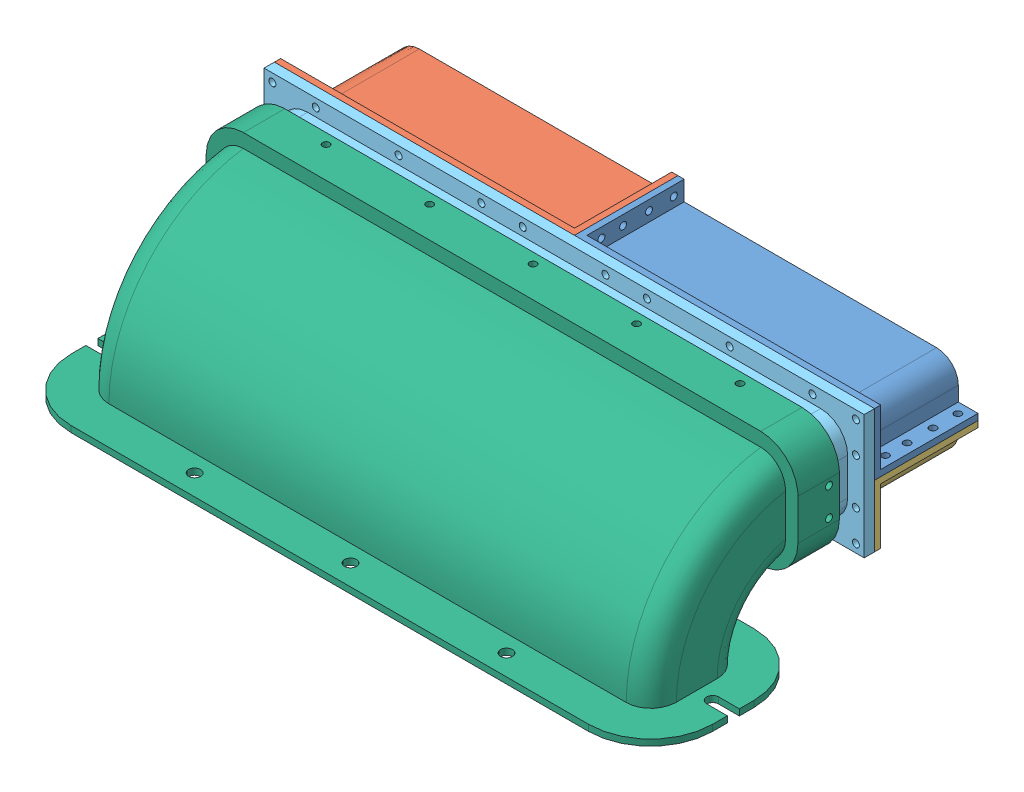
SolidWorks assembly assambly-simflow-HC-4mm, configuration Default. Lengths in mm.
Overall size (310 86 168.23).
9 component instances, 8 part files, 0 mates.
Components (placement in the parent):
- assambly-simflow-HC-4mm.step-1: assambly-simflow-HC-4mm.step [Default] at origin size (315.02 323.76 170.73)
  - HC-4mm-v1_Q1.step-1: HC-4mm-v1_Q1.step [Default] at origin size (145 30 50)
  - HC-4mm-v1_Q2.step-1: HC-4mm-v1_Q2.step [Default] at origin size (145 30 50)
  - HC-4mm-v1_Q1 v1(Mirror).step-1: HC-4mm-v1_Q1 v1(Mirror).step [Default] x (1 0 0) z (0 0 -1) size (145 30 50)
  - HC-4mm-v1_Q2 v1(Mirror).step-1: HC-4mm-v1_Q2 v1(Mirror).step [Default] x (1 0 0) z (0 0 -1) size (145 30 50)
  - adapter.step-1: adapter.step [Default] at (0 0 50) size (290 60 25)
  - main-curved.step-1: main-curved.step [Default] at (0 -56 148.2263) size (310 84 103.23)
  - inlet-adapter.step-1: inlet-adapter.step [Default] at (-0.1461 -136 128.2263) x (1 0 0) z (0 1 0) size (315 85 80) (hidden)
  - inlet-bottom.step-1: inlet-bottom.step [Default] at (-0.1661 -136 128.2263) x (0 0 -1) z (-1 0 0) size (85 158.26 315) (hidden)
